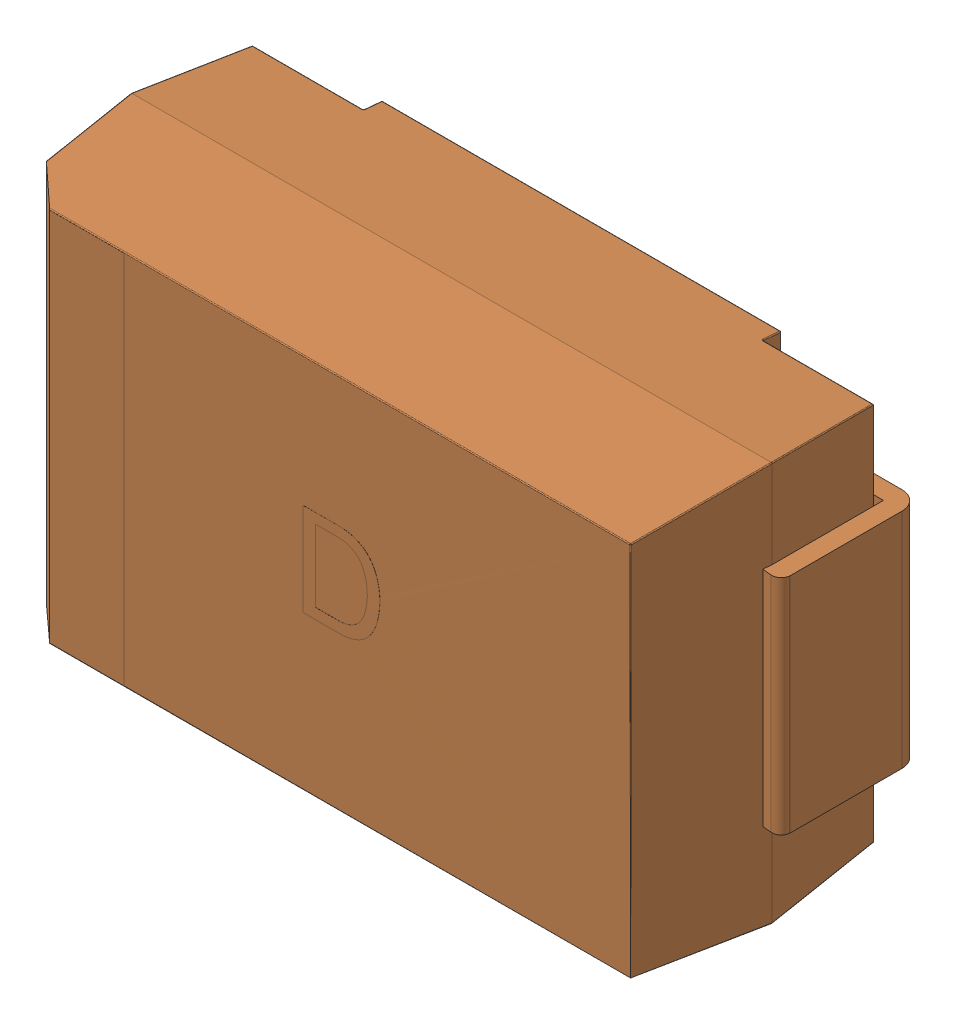
SolidWorks assembly CD_D(7343H), configuration 默认. Lengths in mm.
Overall size (7.3 4.3 2.85).
2 component instances, 2 part files, 0 mates.
Components (placement in the parent):
- LOGO__2-1: LOGO__2 [默认] at (0 0.0355 -0.005) x (-1 0 0) z (0 0 -1) size (1.5 1.73 0.01)
- CD_D(7343)-1: CD_D(7343) [默认] at (0 0 1.4) size (7.3 4.3 2.84)
